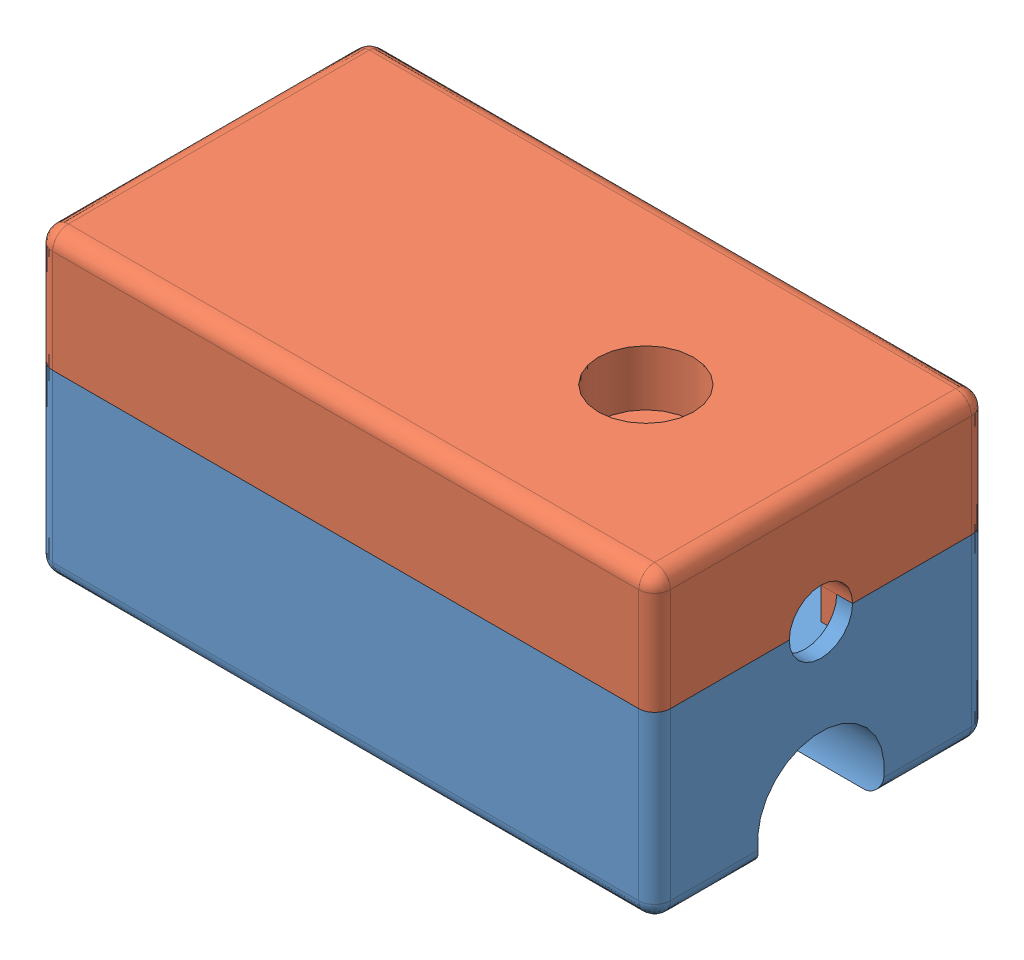
SolidWorks assembly SensorPart, configuration Default. Lengths in mm.
Overall size (39 19 21).
2 component instances, 2 part files, 3 mates.
Components (placement in the parent):
- Part3-1: Part3 [Default] at origin size (39 11.5 21)
- Part4-1: Part4 [Default] at (0 19 -21) x (1 0 0) z (0 0 -1) size (39 9.5 21)
Mates (geometry in assembly coordinates):
- Coincident3: coincident anti-aligned: plane of Part3-1 through (0 11.5 0) normal (0 1 0); plane of Part4-1 through (0 11.5 -21) normal (0 -1 0)
- Coincident4: coincident aligned: plane of Part3-1 through (39 11.5 0) normal (1 0 0); plane of Part4-1 through (39 11.5 -21) normal (1 0 0)
- Coincident5: coincident aligned: plane of Part3-1 through (0 11.5 -21) normal (0 0 -1); plane of Part4-1 through (0 11.5 -21) normal (0 0 -1)
